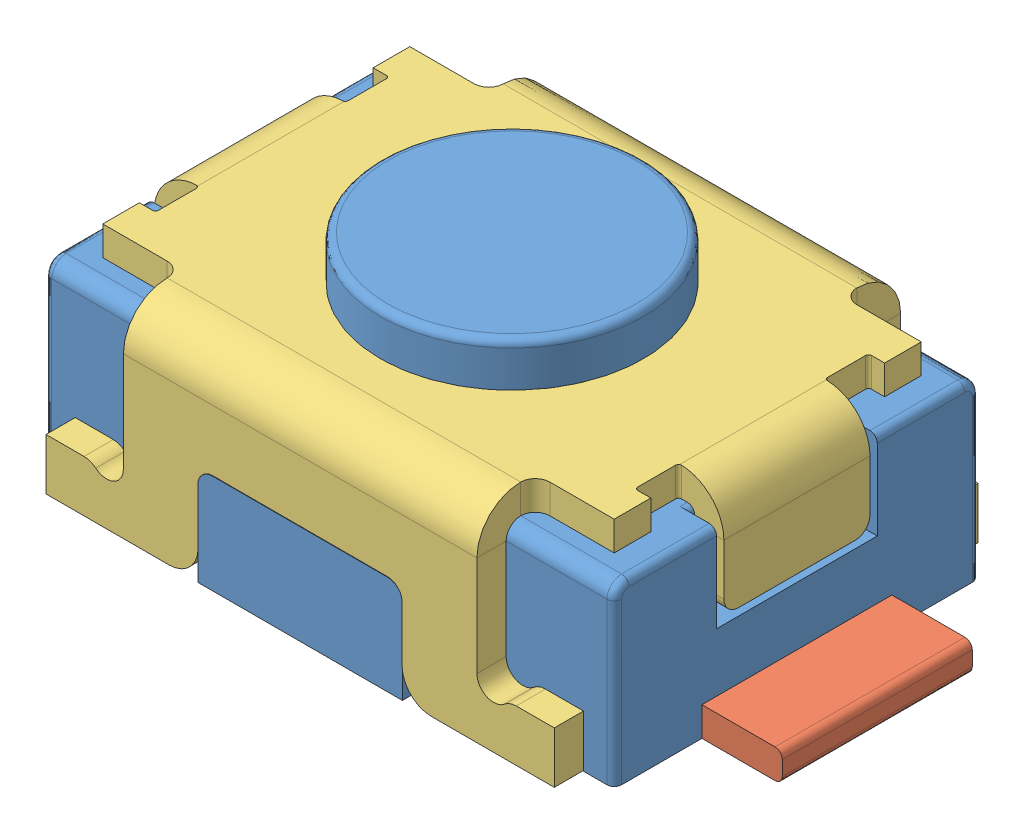
SolidWorks assembly 装配体3, configuration 默认. Lengths in mm.
Overall size (5 1.7 2.9).
4 component instances, 3 part files, 3 mates.
Components (placement in the parent):
- 零件2-2: 零件2 [默认] at (-0.3229 4.9 -0.1566) size (3.9 1.7 2.9)
- 零件3-1: 零件3 [默认] at (-2.2979 3.7 -0.1566) size (1.05 0.2 1.3)
- 零件3-2: 零件3 [默认] at (1.6521 3.7 -0.1566) x (-1 0 0) z (0 0 -1) size (1.05 0.2 1.3)
- 零件1-3: 零件1 [默认] at (-0.3229 4.9 -0.1566) size (3.92 1.41 2.9)
Mates (geometry in assembly coordinates):
- 轮廓中心1: profile center anti-aligned: plane of 零件3-1 through (-1.7729 3.9 -0.8066) normal (1 0 0); plane of 零件2-2 through (-1.7729 3.9 0.4934) normal (-1 0 0)
- 重合1: coincident aligned: circle of 零件2-2; circle of 零件1-3
- 轮廓中心8: profile center anti-aligned: plane of 零件3-2 through (1.1271 3.9 0.4934) normal (-1 0 0); plane of 零件2-2 through (1.1271 3.9 0.4934) normal (1 0 0)
